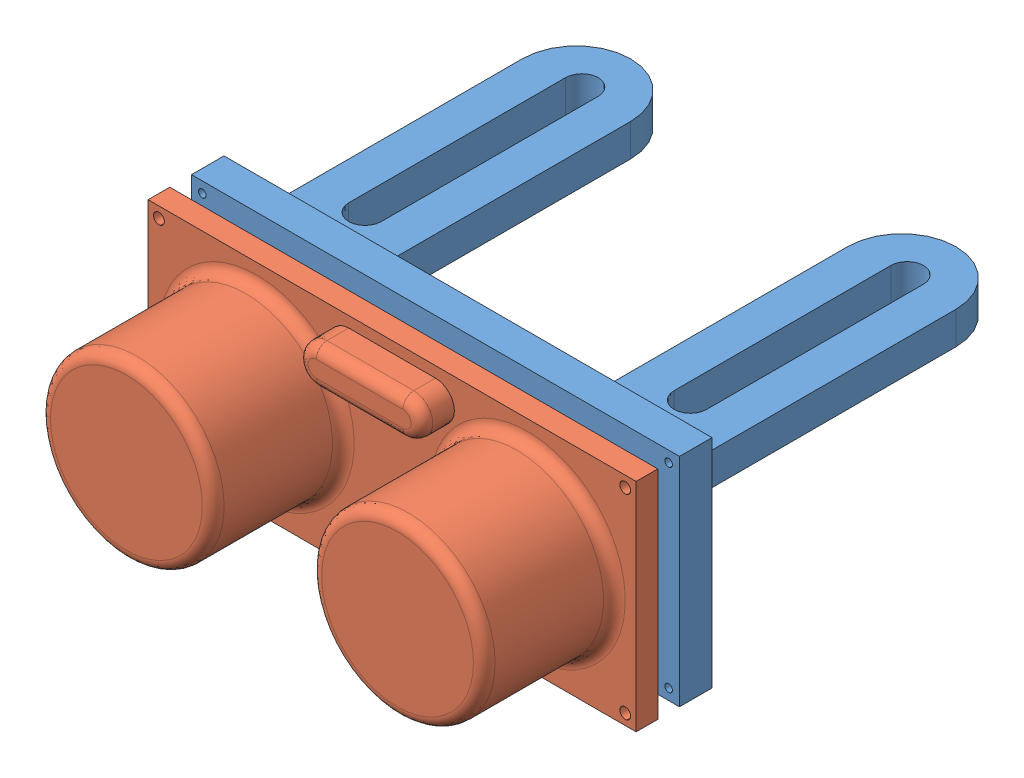
SolidWorks assembly Ultrasonico, configuration Predeterminado. Lengths in mm.
Overall size (45 25.15 49).
2 component instances, 2 part files, 1 mates.
Components (placement in the parent):
- Soporte_ultrasonico-1: Soporte_ultrasonico [Predeterminado] at (-5.581 12.5254 52) size (45 20 33)
- sens_usonic-1: sens_usonic [Predeterminado] at (-5.581 12.5254 57) size (45 25.15 18.54)
Mates (geometry in assembly coordinates):
- CentroDePerfil1: profile center = 2 mm aligned: circle of sens_usonic-1; circle of Soporte_ultrasonico-1
